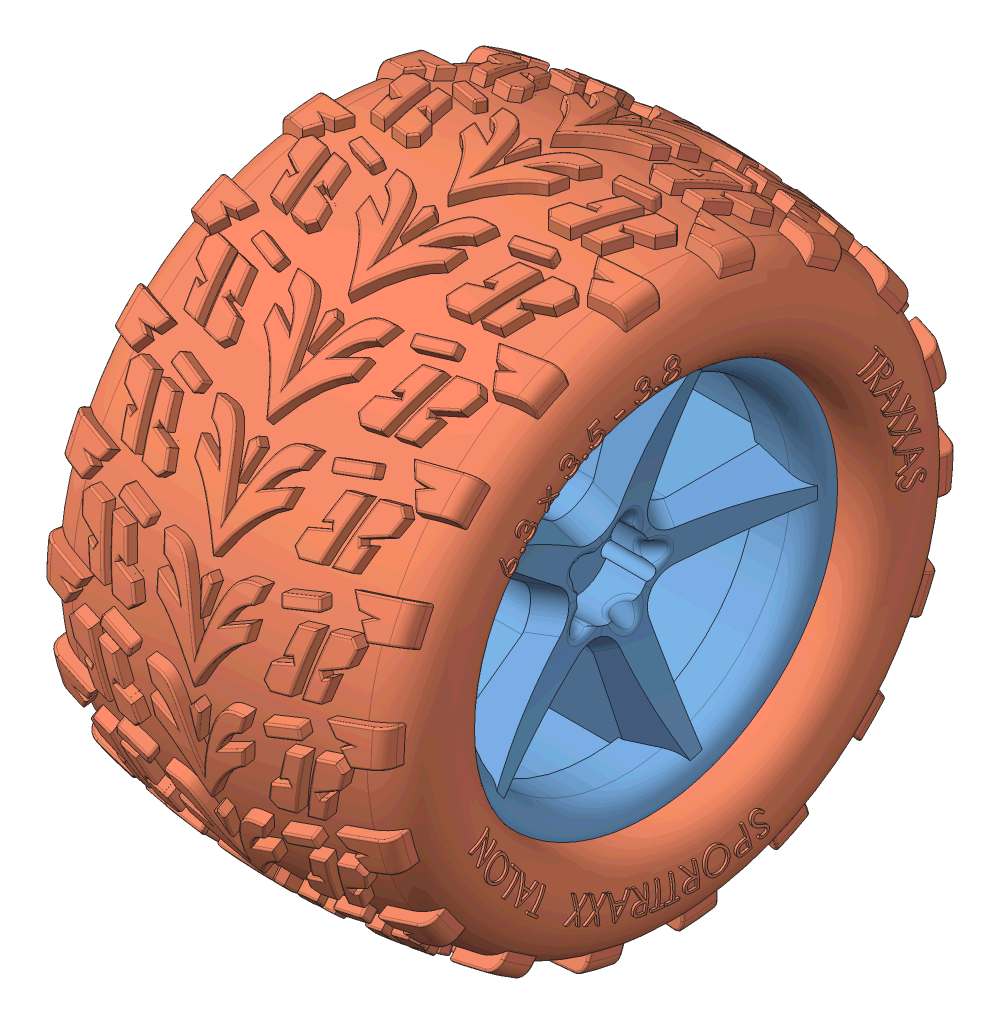
SolidWorks assembly Wheel, configuration Default. Lengths in mm.
Overall size (106.88 166.05 166.47).
2 component instances, 2 part files, 2 mates.
Components (placement in the parent):
- Wheel Rim-1: Wheel Rim [Default] at (-5.7009 62.13 94.8184) size (78.74 101.6 101.6)
- Wheel Tire-1: Wheel Tire [Default] at (-5.7009 62.1295 94.8183) size (106.88 166.05 166.47)
Mates (geometry in assembly coordinates):
- Concentric1: concentric aligned: cylinder of Wheel Rim-1 through (-45.0709 62.13 94.8184) axis (-1 0 0) radius 50.8; cylinder of Wheel Tire-1 through (-45.0732 62.13 94.8184) axis (-1 0 0) radius 50.8
- Coincident1: coincident aligned: plane of Wheel Rim-1 through (-5.7009 62.13 94.8184) normal (1 0 0); plane of Wheel Tire-1 through (-5.7009 62.1295 94.8183) normal (1 0 0)
